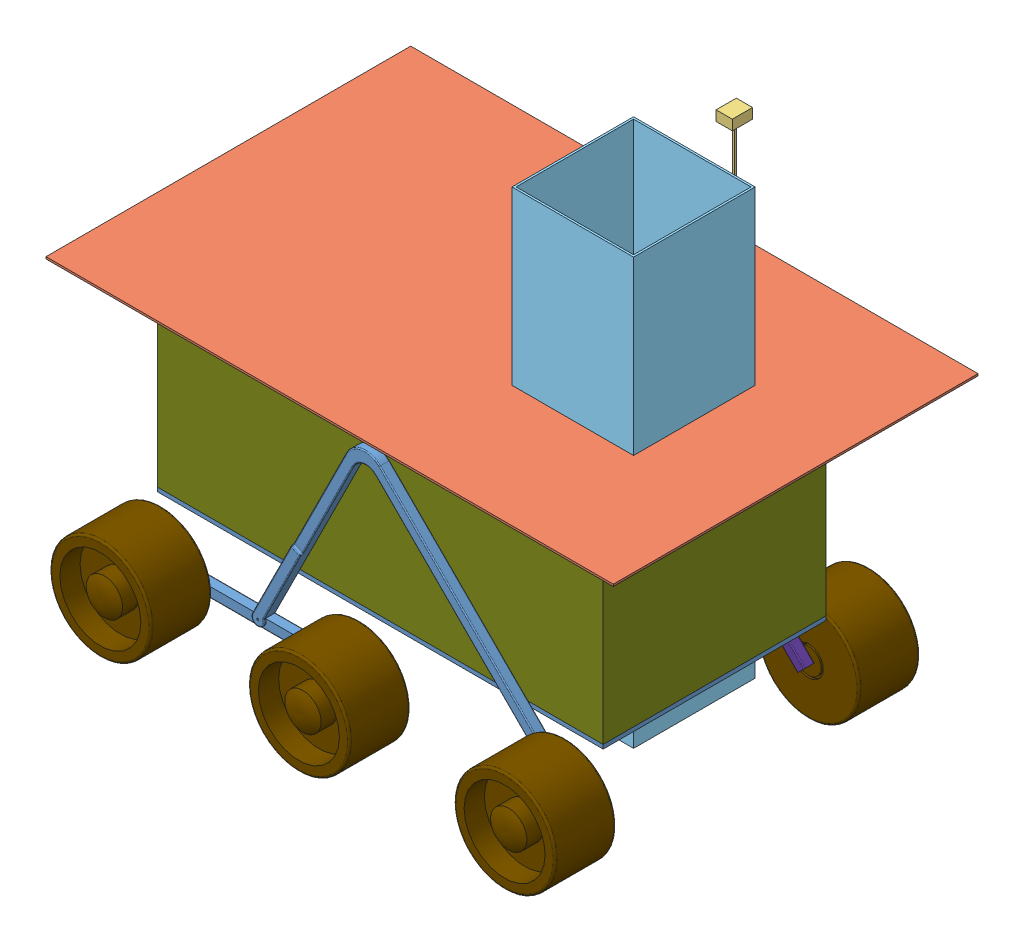
SolidWorks assembly layout_Assem_with_cover, configuration Default. Lengths in mm.
Overall size (2907.8 2551.43 1996.55).
44 component instances, 24 part files, 57 mates.
Components (placement in the parent):
- Rover_base-1: Rover_base [Default] at (-1064.6676 -0.8898 562.4151) size (2200 20 1100)
- Neutron_spectrometer-1: Neutron_spectrometer [Default] at (-926.7762 19.1102 412.2415) size (300 57 300)
- Neutron_spectrometer_electronics-1: Neutron_spectrometer_electronics [Default] at (-664.5809 19.1102 526.5713) size (180 30 130)
- gc-1: gc [Default] at (-1085.6976 19.1102 139.436) size (100 80 100)
- svr_box-1: svr_box [Default] at (435.3324 -172.8625 312.4151) size (600 2100 600)
- xrf-1: xrf [Default] at (-1008.6936 19.1102 -66.8918) size (80 90 80)
- geotechnical_exp-1: geotechnical_exp [Default] at (118.8439 19.1102 479.7148) x (0.999975 0 -0.007135) z (0.007135 0 0.999975) size (130 30 130)
- penetrometer_3-1: penetrometer_3 [Default] at (989.1282 19.1102 -518.5473) x (-0.60186 0 0.798602) z (-0.798602 0 -0.60186) size (20 40 20)
- penetrometer_3-2: penetrometer_3 [Default] at (934.1975 19.1102 -522.9905) size (20 40 20)
- penetrometer_3-3: penetrometer_3 [Default] at (890.3988 19.1102 -523.0172) x (0.957231 0 -0.289323) z (0.289323 0 0.957231) size (20 40 20)
- power-1: power [Default] at (-535.812 19.1102 343.3407) size (180 90 96)
- geotechnical_exp_vane-1: geotechnical_exp_vane [Default] at (965.2252 19.1102 444.9326) size (220 40 220)
- Magnents-1: Magnents [Default] at (-1020.4169 -10.8898 98.2252) size (45 10 45)
- Becon-1: Becon [Default] at (656.9367 19.1102 515.9957) size (80 90 100)
- Belly Cam-1: Belly Cam [Default] at (-660.0101 -90.1314 99.1462) size (150 100 150)
- power_tank-1: power_tank [Default] at (-887.862 555.3324 -63.369) x (-0.812429 0.027314 0.58242) z (0.582091 -0.01957 0.812888) size (1560.46 846.95 1367.46)
  - power_tank_10-1: power_tank_10 [Default] at (-67.1815 281.3265 414.5148) size (500 500 500)
  - power_tank_10-2: power_tank_10 [Default] at (-251.8267 476.4977 723.0274) x (0.786037 -0.315714 0.53148) z (0.083274 0.905991 0.415025) size (500 500 500)
  - power_tank_10-3: power_tank_10 [Default] at (-733.4982 325.3571 380.2859) x (0.665484 -0.133715 0.734337) z (-0.678573 0.301428 0.669836) size (500 500 500)
  - power_tank_10-4: power_tank_10 [Default] at (-1034.3616 424.6302 664.9742) x (0.724325 0.588989 -0.358392) z (-0.233278 0.698521 0.676499) size (500 500 500)
  - power_tank_10-5: power_tank_10 [Default] at (-695.3433 297.5492 1147.5051) x (0.994968 0.097333 0.023775) z (-0.042044 0.190197 0.980845) size (500 500 500)
- Tank_seperator_plate-1: Tank_seperator_plate [Default] at (435.3324 529.1102 512.4151) size (1500 10 1000)
- power_tank-3: power_tank [Default] at (-887.862 502.888 93.4377) x (-0.812429 -0.027314 -0.58242) z (0.582091 0.01957 -0.812888) size (1560.46 846.95 1367.46)
  - power_tank_10-1: power_tank_10 [Default] at (-67.1815 281.3265 414.5148) size (500 500 500)
  - power_tank_10-2: power_tank_10 [Default] at (-251.8267 476.4977 723.0274) x (0.786037 -0.315714 0.53148) z (0.083274 0.905991 0.415025) size (500 500 500)
  - power_tank_10-3: power_tank_10 [Default] at (-733.4982 325.3571 380.2859) x (0.665484 -0.133715 0.734337) z (-0.678573 0.301428 0.669836) size (500 500 500)
  - power_tank_10-4: power_tank_10 [Default] at (-1034.3616 424.6302 664.9742) x (0.724325 0.588989 -0.358392) z (-0.233278 0.698521 0.676499) size (500 500 500)
  - power_tank_10-5: power_tank_10 [Default] at (-695.3433 297.5492 1147.5051) x (0.994968 0.097333 0.023775) z (-0.042044 0.190197 0.980845) size (500 500 500)
- Rover_base_cover-1: Rover_base_cover [Default] at (1135.3324 1069.1102 -537.5849) x (1 0 0) z (0 0 -1) size (2200 1050 1100)
- left_mobiiity_assemSLDASM-1: left_mobiiity_assemSLDASM [Default] at (483.248 -113.7012 -588.2789) x (-1 0 0) z (0 0 -1) size (2699.35 1341.14 400.39)
  - Suspension arms-1: Suspension arms [Default] at (-510.2208 -182.1885 -50.694) size (2035.36 1012.73 130)
  - wheel-1: wheel [Default] at (-515.577 -152.6706 299.306) x (-0.792605 -0.609735 0) z (0 0 -1) size (500 500 300.39)
  - wheel-2: wheel [Default] at (1479.7792 -157.1885 299.306) x (-0.72713 -0.6865 0) z (0 0 -1) size (500 500 300.39)
  - wheel-3: wheel [Default] at (499.7792 -157.1885 299.306) x (-0.949229 -0.314586 0) z (0 0 -1) size (500 500 300.39)
- right_mobiiity_assemSLDASM-1: right_mobiiity_assemSLDASM [Default] at (657.788 -311.6325 815.2315) x (-1 0 0) z (0 0 -1) size (2495.36 1237.73 400.39)
  - Suspension arms_mirror-1: Suspension arms_mirror [Default] at (-335.6808 35.7938 152.8164) size (2035.36 1012.73 130)
  - wheel-1: wheel [Default] at (1654.3192 60.7938 -97.1836) size (500 500 300.39)
  - wheel-2: wheel [Default] at (-341.0371 65.3118 -97.1836) size (500 500 300.39)
  - wheel-3: wheel [Default] at (674.3192 60.7938 -97.1836) size (500 500 300.39)
- solar cell-1: solar cell [Default] at (-1264.6676 1069.1102 -887.5849) x (-1 0 0) z (0 0 -1) size (2800 10 1800)
- stero_imaging_sys-2: stero_imaging_sys [Default] at (325.3324 1059.1102 -537.5849) size (80 548.91 402.36)
- arm-1: arm [Default] at (-1301.9354 19.1102 -517.5849) x (-1 0 0) z (0 0 -1) size (1100 100 100)
- drill-1: drill [Default] at (-665.3253 539.1102 -237.5849) size (500 200 250)
- scoop-1: scoop [Default] at (-1325.6367 25.0847 -517.5849) x (-0.755278 0.655405 0) z (0.655405 0.755278 0) size (211.36 101.82 100)
Mates (geometry in assembly coordinates):
- Coincident2: coincident anti-aligned: plane of Rover_base-1 through (-1064.6676 19.1102 -537.5849) normal (0 1 0); plane of Neutron_spectrometer-1 through (-926.7762 19.1102 412.2415) normal (0 -1 0)
- Coincident6: coincident anti-aligned: plane of Rover_base-1 through (-1064.6676 19.1102 -537.5849) normal (0 1 0); plane of Neutron_spectrometer_electronics-1 through (-664.5809 19.1102 396.5713) normal (0 -1 0)
- Coincident7: coincident anti-aligned: plane of Rover_base-1 through (-1064.6676 19.1102 -537.5849) normal (0 1 0); plane of power-1 through (-535.812 19.1102 247.3407) normal (0 -1 0)
- Coincident8: coincident anti-aligned: plane of Rover_base-1 through (-1064.6676 19.1102 -537.5849) normal (0 1 0); plane of gc-1 through (-1085.6976 19.1102 39.436) normal (0 -1 0)
- Coincident9: coincident aligned: plane of Rover_base-1 through (-1064.6676 19.1102 -537.5849) normal (0 1 0); circle of geotechnical_exp-1 centre (118.8439 19.1102 479.7148) axis (0 1 0)
- Coincident10: coincident anti-aligned: plane of Rover_base-1 through (-1064.6676 19.1102 -537.5849) normal (0 1 0); plane of xrf-1 through (-1008.6936 19.1102 -66.8918) normal (0 -1 0)
- Coincident11: coincident aligned: plane of Rover_base-1 through (-1064.6676 19.1102 -537.5849) normal (0 1 0); circle of penetrometer_3-3 centre (890.3988 19.1102 -523.0172) axis (0 1 0)
- Coincident12: coincident anti-aligned: plane of Rover_base-1 through (-1064.6676 19.1102 -537.5849) normal (0 1 0); plane of penetrometer_3-2 through (934.1975 19.1102 -522.9905) normal (0 -1 0)
- Coincident13: coincident aligned: plane of Rover_base-1 through (-1064.6676 19.1102 -537.5849) normal (0 1 0); circle of penetrometer_3-1 centre (989.1282 19.1102 -518.5473) axis (0 1 0)
- Coincident14: coincident anti-aligned: plane of Rover_base-1 through (-1064.6676 19.1102 -537.5849) normal (0 1 0); plane of geotechnical_exp_vane-1 through (965.2252 19.1102 444.9326) normal (0 -1 0)
- Coincident15: coincident anti-aligned: plane of Rover_base-1 through (-1064.6676 -0.8898 -537.5849) normal (0 -1 0); plane of Magnents-1 through (-1020.4169 -0.8898 98.2252) normal (0 1 0)
- Coincident16: coincident anti-aligned: plane of Rover_base-1 through (-1064.6676 19.1102 -537.5849) normal (0 1 0); plane of Becon-1 through (656.9367 19.1102 515.9957) normal (0 -1 0)
- Tangent1: tangent anti-aligned: plane of Rover_base-1 through (-1064.6676 19.1102 -537.5849) normal (0 1 0); sphere of power_tank-1/power_tank_10-1
- Coincident18: coincident: line of Rover_base-1; plane of svr_box-1 through (435.3324 1927.1375 312.4151) normal (-1 0 0)
- Coincident20: coincident: line of Rover_base-1; plane of svr_box-1 through (435.3324 1927.1375 -287.5849) normal (0 0 -1)
- Perpendicular2: perpendicular: line of Rover_base-1; line of svr_box-1
- Perpendicular3: perpendicular: line of Rover_base-1; line of svr_box-1
- Perpendicular4: perpendicular: line of Rover_base-1; line of svr_box-1
- Tangent12: tangent anti-aligned: plane of Rover_base-1 through (-1064.6676 19.1102 -537.5849) normal (0 1 0); sphere of power_tank-1/power_tank_10-4
- Tangent13: tangent anti-aligned: plane of Rover_base-1 through (-1064.6676 19.1102 -537.5849) normal (0 1 0); sphere of power_tank-1/power_tank_10-5
- Tangent15: tangent anti-aligned: plane of svr_box-1 through (435.3324 1927.1375 312.4151) normal (-1 0 0); sphere of power_tank-1/power_tank_10-4
- Tangent16: tangent anti-aligned: plane of svr_box-1 through (435.3324 1927.1375 312.4151) normal (-1 0 0); sphere of power_tank-1/power_tank_10-5
- Coincident25: coincident anti-aligned: plane of svr_box-1 through (435.3324 1927.1375 312.4151) normal (-1 0 0); plane of Tank_seperator_plate-1 through (435.3324 539.1102 512.4151) normal (1 0 0)
- Parallel1: parallel anti-aligned: plane of Rover_base-1 through (-1064.6676 19.1102 -537.5849) normal (0 1 0); plane of Tank_seperator_plate-1 through (435.3324 529.1102 512.4151) normal (0 -1 0)
- Distance3: distance = 200 mm: line of svr_box-1; point of Tank_seperator_plate-1
- Distance4: distance = 510 mm: plane of Rover_base-1 through (-1064.6676 19.1102 -537.5849) normal (0 1 0); line of Tank_seperator_plate-1
- Tangent29: tangent anti-aligned: plane of svr_box-1 through (435.3324 1927.1375 312.4151) normal (-1 0 0); sphere of power_tank-3/power_tank_10-5
- Tangent30: tangent anti-aligned: plane of svr_box-1 through (435.3324 1927.1375 312.4151) normal (-1 0 0); sphere of power_tank-3/power_tank_10-4
- Tangent32: tangent anti-aligned: plane of Tank_seperator_plate-1 through (435.3324 539.1102 512.4151) normal (0 1 0); sphere of power_tank-3/power_tank_10-1
- Tangent33: tangent anti-aligned: plane of Tank_seperator_plate-1 through (435.3324 539.1102 512.4151) normal (0 1 0); sphere of power_tank-3/power_tank_10-4
- Tangent34: tangent anti-aligned: plane of Tank_seperator_plate-1 through (435.3324 539.1102 512.4151) normal (0 1 0); sphere of power_tank-3/power_tank_10-5
- Coincident33: coincident anti-aligned: plane of svr_box-1 through (435.3324 1927.1375 -287.5849) normal (0 0 -1); plane of Rover_base_cover-1 through (1035.3324 669.1102 -287.5849) normal (0 0 1)
- Coincident34: coincident anti-aligned: plane of svr_box-1 through (435.3324 1927.1375 312.4151) normal (-1 0 0); plane of Rover_base_cover-1 through (435.3324 669.1102 -287.5849) normal (1 0 0)
- Coincident35: coincident anti-aligned: plane of Rover_base-1 through (-1064.6676 19.1102 -537.5849) normal (0 1 0); plane of Rover_base_cover-1 through (1135.3324 19.1102 562.4151) normal (0 -1 0)
- Coincident36: coincident anti-aligned: plane of Rover_base_cover-1 through (1135.3324 19.1102 -537.5849) normal (0 0 -1); plane of left_mobiiity_assemSLDASM-1/Suspension arms-1 through (8.4233 612.8524 -537.5849) normal (0 0 1)
- Parallel2: parallel anti-aligned: line of Rover_base-1; line of left_mobiiity_assemSLDASM-1/Suspension arms-1
- Coincident37: coincident anti-aligned: plane of Rover_base_cover-1 through (1135.3324 19.1102 562.4151) normal (0 0 1); plane of right_mobiiity_assemSLDASM-1/Suspension arms_mirror-1 through (8.4233 632.9035 562.4151) normal (0 0 -1)
- Parallel3: parallel anti-aligned: line of Rover_base_cover-1; line of right_mobiiity_assemSLDASM-1/Suspension arms_mirror-1
- Distance6: distance = 250 mm: line of Rover_base-1; line of right_mobiiity_assemSLDASM-1/Suspension arms_mirror-1
- Distance8: distance = 250 mm: line of Rover_base-1; line of left_mobiiity_assemSLDASM-1/Suspension arms-1
- Distance9: distance = 725 mm: line of Rover_base_cover-1; point of right_mobiiity_assemSLDASM-1/Suspension arms_mirror-1
- Distance10: distance = 725 mm: line of Rover_base_cover-1; point of left_mobiiity_assemSLDASM-1/Suspension arms-1
- Coincident45: coincident anti-aligned: plane of Rover_base_cover-1 through (1135.3324 1069.1102 562.4151) normal (0 1 0); plane of solar cell-1 through (-1264.6676 1069.1102 -887.5849) normal (0 -1 0)
- Coincident46: coincident anti-aligned: plane of svr_box-1 through (435.3324 1927.1375 312.4151) normal (-1 0 0); plane of solar cell-1 through (435.3324 1069.1102 -287.5849) normal (1 0 0)
- Coincident47: coincident anti-aligned: plane of svr_box-1 through (435.3324 1927.1375 312.4151) normal (0 0 1); plane of solar cell-1 through (435.3324 1069.1102 312.4151) normal (0 0 -1)
- Coincident50: coincident anti-aligned: plane of solar cell-1 through (-1264.6676 1069.1102 -887.5849) normal (0 -1 0); plane of stero_imaging_sys-2 through (335.3324 1069.1102 -884.9456) normal (0 1 0)
- Coincident51: coincident anti-aligned: plane of Rover_base_cover-1 through (1135.3324 19.1102 -537.5849) normal (0 0 -1); plane of stero_imaging_sys-2 through (335.3324 1069.1102 -537.5849) normal (0 0 1)
- Distance12: distance = 800 mm: line of Rover_base_cover-1; line of stero_imaging_sys-2
- Coincident54: coincident anti-aligned: plane of Rover_base-1 through (-1064.6676 19.1102 -537.5849) normal (0 1 0); plane of arm-1 through (-1301.9354 19.1102 -417.5849) normal (0 -1 0)
- Parallel4: parallel aligned: plane of Rover_base-1 through (-1064.6676 19.1102 -537.5849) normal (0 0 -1); plane of arm-1 through (-1301.9354 119.1102 -517.5849) normal (0 0 -1)
- Distance13: distance = 20 mm aligned: plane of Rover_base-1 through (-1064.6676 19.1102 -537.5849) normal (0 0 -1); plane of arm-1 through (-1301.9354 119.1102 -517.5849) normal (0 0 -1)
- Distance14: distance = 200 mm: plane of Rover_base-1 through (-1064.6676 19.1102 562.4151) normal (-1 0 0); point of arm-1
- Coincident58: coincident anti-aligned: plane of Tank_seperator_plate-1 through (435.3324 539.1102 512.4151) normal (0 1 0); plane of drill-1 through (-665.3253 539.1102 -487.5849) normal (0 -1 0)
- Coincident59: coincident aligned: plane of Tank_seperator_plate-1 through (435.3324 539.1102 -487.5849) normal (0 0 -1); plane of drill-1 through (-665.3253 739.1102 -487.5849) normal (0 0 -1)
- Distance15: distance = 100.6577 mm aligned: plane of Tank_seperator_plate-1 through (-1064.6676 539.1102 512.4151) normal (-1 0 0); plane of drill-1 through (-1165.3253 739.1102 -237.5849) normal (-1 0 0)
- Concentric2: concentric aligned: cylinder of arm-1; cylinder of scoop-1
- Coincident61: coincident anti-aligned: plane of arm-1 through (-1301.9354 119.1102 -467.5849) normal (0 0 1); plane of scoop-1 through (-1285.4631 22.5198 -467.5849) normal (0 0 -1)
